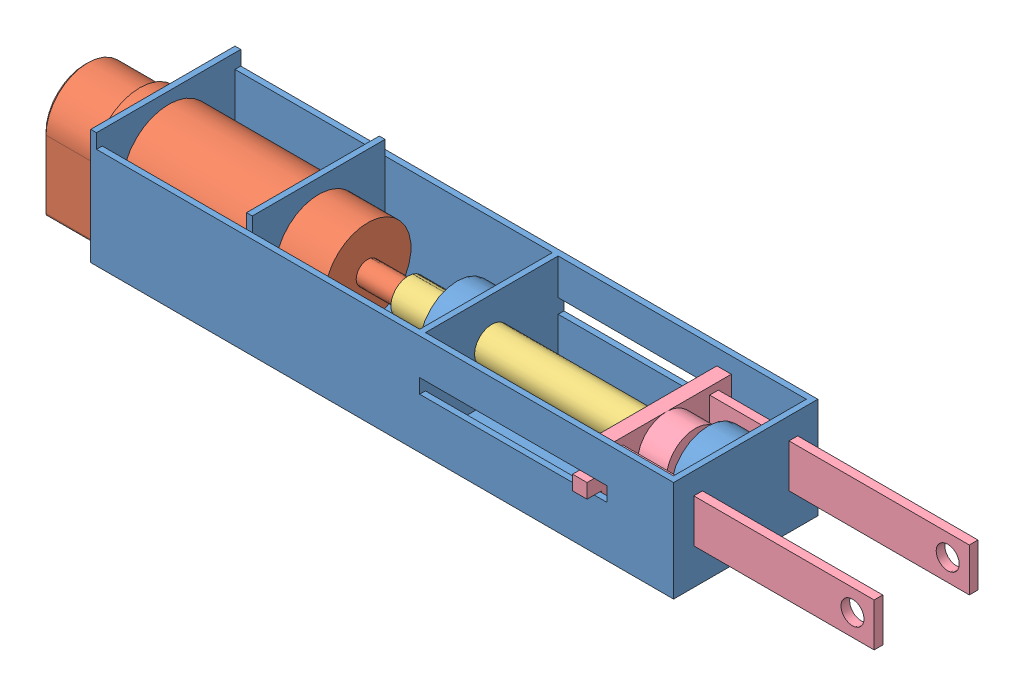
SolidWorks assembly Combine, configuration 預設. Lengths in mm.
Overall size (291.5 44.5 55).
4 component instances, 4 part files, 8 mates.
Components (placement in the parent):
- Settle-1: Settle [預設] at (3.399 62.4897 105.7634) size (202 40 50)
- Motor-1: Motor [預設] at (-161.601 82.4897 105.7634) x (0 0 1) z (1 0 0) size (32 40.5 112)
- Screw-1: Screw [預設] at (46.399 82.4897 105.7634) x (0 0 1) z (-1 0 0) size (12 12 115)
- Dragger-1: Dragger [預設] at (20.8984 82.4897 105.7634) x (0 0 1) z (-1 0 0) size (55 20 95)
Mates (geometry in assembly coordinates):
- 同軸心1: concentric: cylinder of Settle-1 through (-153.601 82.4897 105.7634) axis (1 0 0) radius 16; cylinder of Motor-1 through (-82.601 82.4897 105.7634) axis (-1 0 0) radius 16
- 重合/共線/共點1: coincident: circle of Motor-1; circle of Screw-1
- 重合/共線/共點2: coincident: plane of Settle-1 through (46.399 65.4897 128.7634) normal (-1 0 0); plane of Screw-1 through (46.399 82.4897 105.7634) normal (1 0 0)
- 同軸心2: concentric: cylinder of Screw-1 through (-68.601 82.4897 105.7634) axis (1 0 0) radius 6; cylinder of Dragger-1 through (15.8984 82.4897 105.7634) axis (1 0 0) radius 6
- 重合/共線/共點3: coincident: plane of Settle-1 through (25.399 79.9897 130.7634) normal (0 1 0); plane of Dragger-1 through (15.8984 79.9897 128.2634) normal (0 -1 0)
- 重合/共線/共點4: coincident: plane of Motor-1 through (-68.601 82.4897 105.7634) normal (1 0 0); plane of Screw-1 through (-68.601 82.4897 105.7634) normal (-1 0 0)
- 平行1: parallel: plane of Settle-1 through (3.399 62.4897 105.7634) normal (0 -1 0); plane of Motor-1 through (-180.601 57.9897 92.2634) normal (0 -1 0)
- 同軸心3: concentric: cylinder of Settle-1 through (-22.6304 82.4897 105.7634) axis (-1 0 0) radius 6; cylinder of Screw-1 through (-68.601 82.4897 105.7634) axis (1 0 0) radius 6
